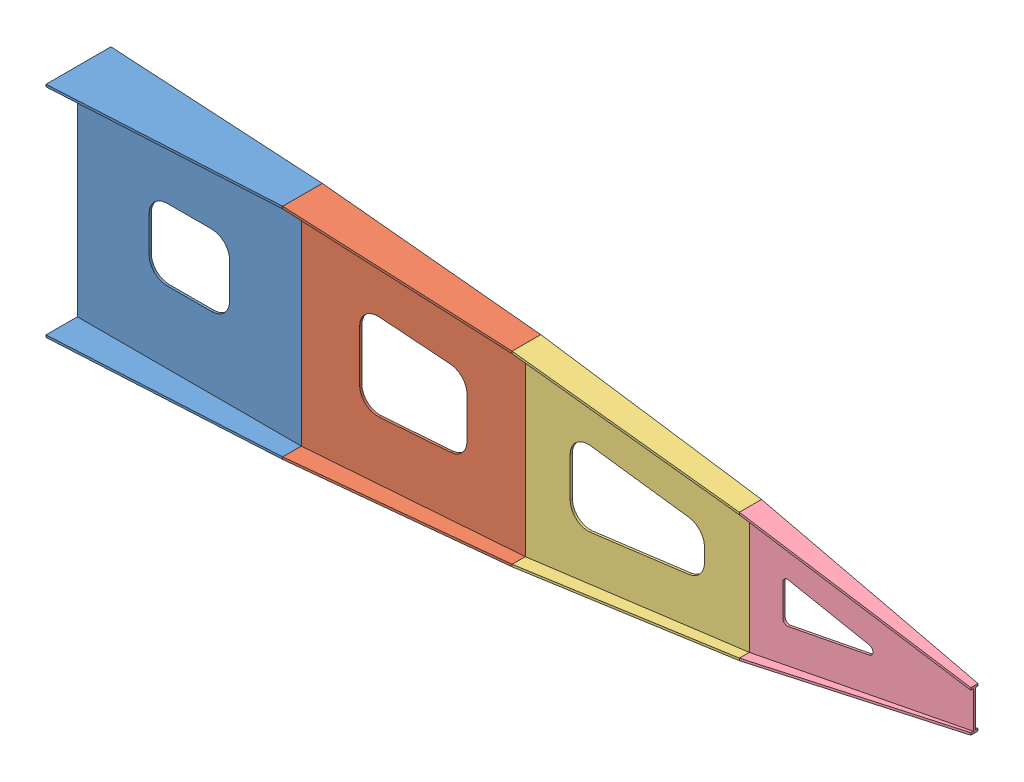
SolidWorks assembly 1.10 tolerance assembly, configuration Default. Lengths in mm.
Overall size (4000 979 290).
4 component instances, 4 part files, 9 mates.
Components (placement in the parent):
- 1-1: 1 [Default] at (-775.9263 612.0858 1043.8579) size (1000 979 290)
- 2-2: 2 [Default] at (224.0737 612.0858 1043.8579) size (1000 979 177)
- 3-2: 3 [Default] at (1224.0737 612.0858 1043.8579) size (1000 834 128)
- 4-2: 4 [Default] at (2224.0737 612.0858 1043.8579) size (1000 574 99)
Mates (geometry in assembly coordinates):
- Coincident39: coincident anti-aligned: plane of 1-1 through (224.0737 612.0858 1043.8579) normal (1 0 0); plane of 2-2 through (224.0737 612.0858 1043.8579) normal (-1 0 0)
- Coincident40: coincident anti-aligned: plane of 2-2 through (1224.0737 612.0858 1043.8579) normal (1 0 0); plane of 3-2 through (1224.0737 612.0858 1043.8579) normal (-1 0 0)
- Coincident42: coincident: point of 1-1; point of 2-2
- Coincident43: coincident: point of 1-1; point of 2-2
- Coincident44: coincident: point of 2-2; point of 3-2
- Coincident46: coincident: point of 2-2; point of 3-2
- Coincident49: coincident: point of 3-2; point of 4-2
- Coincident52: coincident aligned: plane of 3-2 through (1224.0737 612.0858 1053.8579) normal (0 0 1); plane of 4-2 through (2224.0737 612.0858 1053.8579) normal (0 0 1)
- Coincident53: coincident: point of 3-2; point of 4-2
